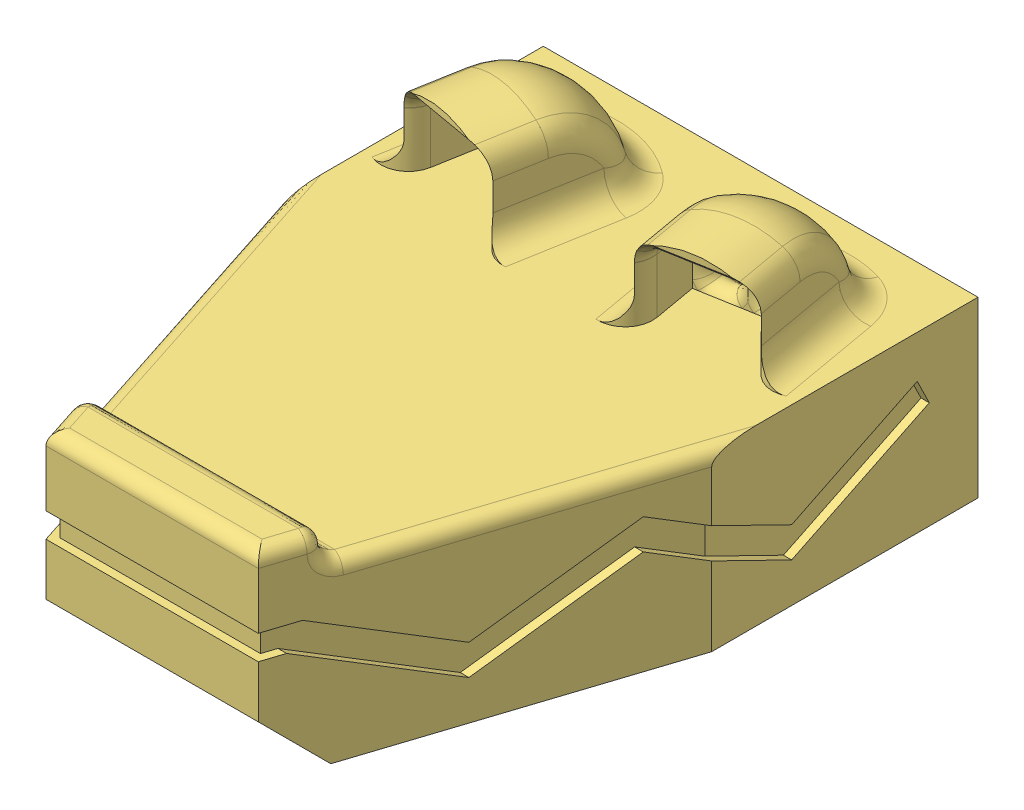
SolidWorks assembly GatorHead Assem, configuration Default. Lengths in mm.
Overall size (31.75 20.5 44.45).
3 component instances, 3 part files, 7 mates.
Components (placement in the parent):
- ServoHead-1: ServoHead [Default] at origin size (27 5.5 37.18)
- SampleCircuitBoard-1: SampleCircuitBoard [Default] at (0 5.5 -3) size (23 1.5 22)
- GatorHead-1: GatorHead [Default] at (0 1.3 8.225) size (31.75 19.2 44.45)
Mates (geometry in assembly coordinates):
- Coincident1: coordinate: point of ServoHead-1
- Coincident3: coincident aligned: plane of ServoHead-1 through (0 0 0) normal (1 0 0); plane of SampleCircuitBoard-1 through (0 5.5 -3) normal (1 0 0)
- Coincident4: coincident aligned: plane of SampleCircuitBoard-1 through (0 5.5 -3) normal (1 0 0); plane of GatorHead-1 through (0 1.3 8.225) normal (1 0 0)
- Coincident5: coincident anti-aligned: plane of SampleCircuitBoard-1 through (0 7 -3) normal (0 1 0); plane of GatorHead-1 through (0 7 8.225) normal (0 -1 0)
- Coincident7: coincident aligned: plane of SampleCircuitBoard-1 through (-11.5 7 -14) normal (0 0 -1); plane of GatorHead-1 through (-15.875 14 -14) normal (0 0 -1)
- Coincident10: coincident anti-aligned: plane of ServoHead-1 through (0 5.5 0) normal (0 1 0); plane of SampleCircuitBoard-1 through (0 5.5 -3) normal (0 -1 0)
- Coincident12: coincident aligned: plane of ServoHead-1 through (-13.5 5.5 -14) normal (0 0 -1); plane of GatorHead-1 through (-15.875 14 -14) normal (0 0 -1)
